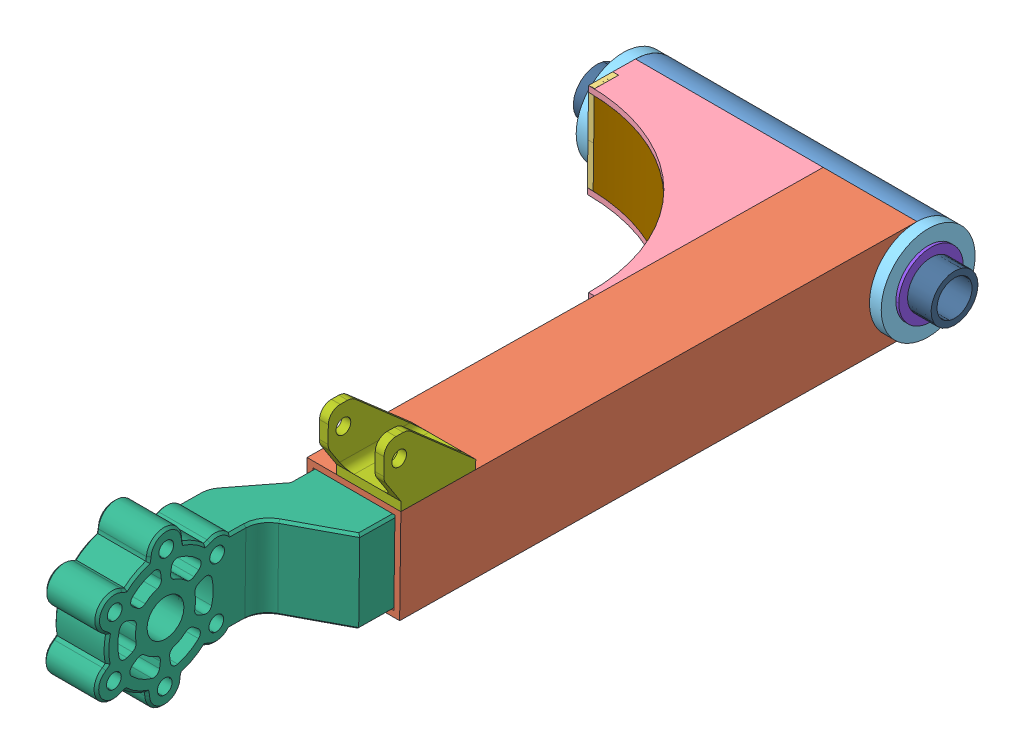
SolidWorks assembly Suspension set 2, configuration Default. Lengths in mm.
Overall size (193.67 103.89 441.92).
16 component instances, 13 part files, 36 mates.
Components (placement in the parent):
- SR 1 (2 inch)-1: SR 1 (2 inch) [Default] at (-137.0883 -10.8304 39.4879) size (152.4 50.8 50.8)
- SR (square tube)-1: SR (square tube) [Default] at (-10.0883 -10.8304 39.4879) x (1 0 0) z (0 0.013285 0.999912) size (50.8 50.8 279.4)
- Part1^Suspension set 2-1: Part1^Suspension set 2 [Default] at origin (virtual)
- Part2^Suspension set 2-1: Part2^Suspension set 2 [Default] at (-10.0883 14.5674 39.1505) x (1 0 0) z (0 0.999912 -0.013285) (virtual)
- Part3^Suspension set 2-1: Part3^Suspension set 2 [Default] at (-137.0883 -10.8304 39.4879) x (0 0 1) z (-1 0 0) size (13.73 50.97 3.17) (virtual)
- Part4^Suspension set 2-1: Part4^Suspension set 2 [Default] at origin (virtual)
- Gusset Rear Suspension set 2-1: Gusset Rear Suspension set 2 [Default] at (-65.1345 15.7769 130.1824) x (1 0 0) z (0 0.999912 -0.013285) size (101.6 123.82 3.17)
- Gusset Rear Suspension set 2-2: Gusset Rear Suspension set 2 [Default] at (-65.1345 -31.8439 130.8151) x (1 0 0) z (0 0.999912 -0.013285) size (101.6 123.82 3.17)
- SR (Cap)-1: SR (Cap) [Default] at (-143.4383 -10.8304 39.4879) x (-1 0 0) z (0 -0.74503 0.667031) size (19.05 50.8 50.8)
- SR (Cap)-2: SR (Cap) [Default] at (21.6617 -10.8304 39.4879) size (19.05 50.8 50.8)
- Cap insert-1: Cap insert [Default] at (12.1367 -29.1729 331.8574) x (-1 0 0) z (0 -0.013285 -0.999912) size (63.5 83.05 151.54)
- Brake Bracket-1: Brake Bracket [Default] at (-2.1508 22.8357 302.9889) x (-1 0 0) z (0 0.013285 0.999912) size (34.92 36.51 50)
- JFI-1618-12-1: JFI-1618-12 [Default] at (-145.0131 -10.8304 39.4879) x (0 0 -1) z (1 0 0) size (34.92 34.92 19.05)
- JFI-1618-12-2: JFI-1618-12 [Default] at (23.2365 -10.8304 39.4879) x (0 0 1) z (-1 0 0) size (34.92 34.92 19.05)
- Part5^Suspension set 2-1: Part5^Suspension set 2 [Default] at (-65.1345 -31.8439 130.8151) x (1 0 0) z (0 0.999912 -0.013285) size (98.42 101.55 44.45) (virtual)
- SR (axel)-1: SR (axel) [Default] at (-157.7258 -10.8304 39.4879) x (1 0 0) z (0 -0.238586 0.971121) size (193.68 25.4 25.4)
Mates (geometry in assembly coordinates):
- Concentric1: concentric anti-aligned: cylinder of SR 1 (2 inch)-1 through (15.3117 -10.8304 39.4879) axis (-1 0 0) radius 25.4; cylinder of SR (square tube)-1 through (-149.7883 -10.8304 39.4879) axis (1 0 0) radius 25.4
- Coincident1: coincident aligned: plane of SR 1 (2 inch)-1 through (15.3117 -10.8304 39.4879) normal (1 0 0); plane of SR (square tube)-1 through (15.3117 -32.5163 319.2007) normal (1 0 0)
- InPlace1: in place: plane of SR (square tube)-1 through (-35.4883 18.2792 318.5258) normal (0 0.999912 -0.013285); plane of ? through (0 14.0448 -0.1866) normal (0 0.999912 -0.013285); moOrthogonalPlaneRef_w of SR (square tube)-1 through (-35.4883 18.2792 318.5258) normal (0 0.999912 -0.013285); plane of ? through (0 14.0448 -0.1866) normal (0 -0.013285 -0.999912); plane of SR (square tube)-1 through (-35.4883 18.2792 318.5258) normal (0 0.999912 -0.013285); plane of ? through (0 14.0448 -0.1866) normal (1 0 0); plane of SR (square tube)-1 through (-35.4883 18.2792 318.5258) normal (0 0.999912 -0.013285); unknown of Part2^Suspension set 2-1
- Coincident2: coincident aligned: plane of SR (square tube)-1; plane of Part2^Suspension set 2-1
- Coincident3: coincident aligned: moOrthogonalPlaneRef_w of SR (square tube)-1 through (-10.0883 14.5674 39.1505) normal (0 -0.013285 -0.999912); plane of Part2^Suspension set 2-1 through (-10.0883 14.5674 39.1505) normal (0 -0.013285 -0.999912)
- Coincident4: coincident anti-aligned: moOrthogonalPlaneRef_w of SR (square tube)-1 through (-10.0883 14.5674 39.1505) normal (-1 0 0); plane of Part2^Suspension set 2-1 through (-10.0883 14.5674 39.1505) normal (1 0 0)
- InPlace2: in place: plane of SR 1 (2 inch)-1 through (-137.0883 -10.8304 39.4879) normal (-1 0 0); plane of ? through (-137.0883 0 0) normal (-1 0 0); plane of SR 1 (2 inch)-1 through (-137.0883 -10.8304 39.4879) normal (-1 0 0); plane of ? through (-137.0883 0 0) normal (0 1 0); plane of SR 1 (2 inch)-1 through (-137.0883 -10.8304 39.4879) normal (-1 0 0); plane of ? through (-137.0883 0 0) normal (0 0 1); plane of SR 1 (2 inch)-1 through (-137.0883 -10.8304 39.4879) normal (-1 0 0); unknown of Part3^Suspension set 2-1
- Coincident5: coincident aligned: plane of SR 1 (2 inch)-1; plane of Part3^Suspension set 2-1
- Coincident6: coincident aligned: moOrthogonalPlaneRef_w of SR 1 (2 inch)-1 through (-137.0883 -10.8304 39.4879) normal (0 1 0); plane of Part3^Suspension set 2-1 through (-137.0883 -10.8304 39.4879) normal (0 1 0)
- Coincident7: coincident anti-aligned: moOrthogonalPlaneRef_w of SR 1 (2 inch)-1 through (-137.0883 -10.8304 39.4879) normal (0 0 -1); plane of Part3^Suspension set 2-1 through (-137.0883 -10.8304 39.4879) normal (0 0 1)
- Coincident13: coincident anti-aligned: line of Part3^Suspension set 2-1 through (-137.0883 14.9048 64.5482) axis (0 -0.013285 -0.999912); line of Gusset Rear Suspension set 2-1 through (-137.0883 14.5674 39.1505) axis (0 0.013285 0.999912)
- Coincident26: coincident anti-aligned: line of Part3^Suspension set 2-1 through (-137.0883 -35.8907 65.2231) axis (0 -0.013285 -0.999912); line of Gusset Rear Suspension set 2-2 through (-137.0883 -36.2281 39.8253) axis (0 0.013285 0.999912)
- Coincident34: coincident aligned: plane of Part3^Suspension set 2-1 through (-137.0883 -10.8304 39.4879) normal (-1 0 0); plane of Gusset Rear Suspension set 2-2 through (-137.0883 -36.2281 39.8253) normal (-1 0 0)
- Coincident44: coincident anti-aligned: plane of SR 1 (2 inch)-1 through (-137.0883 -10.8304 39.4879) normal (-1 0 0); plane of SR (Cap)-1 through (-137.0883 -27.7729 20.5641) normal (1 0 0)
- Concentric2: concentric aligned: cylinder of SR 1 (2 inch)-1 through (15.3117 -10.8304 39.4879) axis (-1 0 0) radius 22.225; cylinder of SR (Cap)-1 through (-143.4383 -10.8304 39.4879) axis (-1 0 0) radius 22.225
- Concentric3: concentric anti-aligned: cylinder of SR 1 (2 inch)-1 through (15.3117 -10.8304 39.4879) axis (-1 0 0) radius 22.225; cylinder of SR (Cap)-2 through (21.6617 -10.8304 39.4879) axis (1 0 0) radius 22.225
- Coincident45: coincident anti-aligned: plane of SR 1 (2 inch)-1 through (15.3117 -10.8304 39.4879) normal (1 0 0); plane of SR (Cap)-2 through (15.3117 14.5696 39.4879) normal (-1 0 0)
- Coincident48: coincident anti-aligned: plane of SR (square tube)-1 through (-32.3133 -29.3416 319.1585) normal (1 0 0); plane of Cap insert-1 through (-32.3133 -29.679 293.7607) normal (-1 0 0)
- Coincident49: coincident anti-aligned: plane of SR (square tube)-1 through (-32.3133 15.1045 318.568) normal (0 -0.999912 0.013285); plane of Cap insert-1 through (12.1367 14.767 293.1702) normal (0 0.999912 -0.013285)
- Distance1: distance = 25.4 mm anti-aligned: plane of Cap insert-1 through (12.1367 -29.679 293.7607) normal (0 -0.013285 -0.999912); plane of SR (square tube)-1 through (-10.0883 -7.1186 318.8632) normal (0 0.013285 0.999912)
- Coincident51: coincident anti-aligned: plane of SR (square tube)-1 through (-35.4883 18.2792 318.5258) normal (0 0.999912 -0.013285); plane of Brake Bracket-1 through (-2.1508 18.0736 303.0522) normal (0 -0.999912 0.013285)
- Coincident52: coincident anti-aligned: line of SR (square tube)-1 through (15.3117 18.2792 318.5258) axis (0 -0.013285 -0.999912); line of Brake Bracket-1 through (15.3117 17.7415 278.0544) axis (0 0.013285 0.999912)
- Coincident53: coincident aligned: line of SR (square tube)-1 through (15.3117 18.2792 318.5258) axis (-1 0 0); line of Brake Bracket-1 through (15.3117 18.2792 318.5258) axis (-1 0 0)
- Coincident54: coincident anti-aligned: plane of SR (Cap)-1 through (-143.4383 -20.3606 28.8433) normal (-1 0 0); plane of JFI-1618-12-1 through (-143.4383 -10.8304 23.3629) normal (1 0 0)
- Concentric4: concentric anti-aligned: cylinder of SR (Cap)-1 through (-143.4383 -10.8304 39.4879) axis (-1 0 0) radius 14.2875; cylinder of JFI-1618-12-1 through (-135.4881 -10.8304 39.4879) axis (1 0 0) radius 12.7
- Coincident55: coincident anti-aligned: plane of SR (Cap)-2 through (21.6617 3.4571 39.4879) normal (1 0 0); plane of JFI-1618-12-2 through (21.6617 -10.8304 55.6129) normal (-1 0 0)
- Concentric5: concentric anti-aligned: cylinder of SR (Cap)-2 through (21.6617 -10.8304 39.4879) axis (1 0 0) radius 14.2875; cylinder of JFI-1618-12-2 through (13.0741 -10.8304 39.4879) axis (-1 0 0) radius 14.2875
- Coincident56: coincident aligned: line of Part3^Suspension set 2-1 through (-133.9133 -10.4929 64.8857) axis (0 -0.999912 0.013285); line of Part7^Suspension set 2-1 through (-133.9133 11.7301 64.5904) axis (0 -0.999912 0.013285)
- Coincident59: coincident anti-aligned: plane of Gusset Rear Suspension set 2-1 through (-137.0883 13.0377 163.0067) normal (0 -0.999912 0.013285); plane of Part7^Suspension set 2-1 through (-137.0883 13.0377 163.0067) normal (0 0.999912 -0.013285)
- Coincident60: coincident anti-aligned: line of SR (square tube)-1 through (-35.4883 -36.2281 39.8253) axis (1 0 0); line of Gusset Rear Suspension set 2-2 through (-35.4883 -36.2281 39.8253) axis (-1 0 0)
- InPlace3: in place: plane of ? through (-137.0883 -31.4084 163.5972) normal (0 0.999912 -0.013285); plane of ? through (0 -33.576 0.4461) normal (0 0.999912 -0.013285); plane of ? through (-137.0883 -31.4084 163.5972) normal (0 0.999912 -0.013285); plane of ? through (0 -33.576 0.4461) normal (0 -0.013285 -0.999912); plane of ? through (-137.0883 -31.4084 163.5972) normal (0 0.999912 -0.013285); plane of ? through (0 -33.576 0.4461) normal (1 0 0); plane of ? through (-137.0883 -31.4084 163.5972) normal (0 0.999912 -0.013285); unknown of ?
- Coincident61: coincident aligned: plane of Gusset Rear Suspension set 2-2; plane of Part5^Suspension set 2-1
- Coincident62: coincident aligned: moOrthogonalPlaneRef_w of Gusset Rear Suspension set 2-2 through (-65.1345 -31.8439 130.8151) normal (0 -0.013285 -0.999912); plane of Part5^Suspension set 2-1 through (-65.1345 -31.8439 130.8151) normal (0 -0.013285 -0.999912)
- Coincident63: coincident anti-aligned: moOrthogonalPlaneRef_w of Gusset Rear Suspension set 2-2 through (-65.1345 -31.8439 130.8151) normal (-1 0 0); plane of Part5^Suspension set 2-1 through (-65.1345 -31.8439 130.8151) normal (1 0 0)
- Concentric6: concentric anti-aligned: cylinder of JFI-1618-12-1 through (-135.4881 -10.8304 39.4879) axis (1 0 0) radius 12.7; cylinder of SR (axel)-1 through (35.9492 -10.8304 39.4879) axis (-1 0 0) radius 12.7
- Distance2: distance = 14.2875 mm aligned: plane of SR (axel)-1 through (-157.7258 -10.8304 39.4879) normal (-1 0 0); plane of SR (Cap)-1 through (-143.4383 -20.3606 28.8433) normal (-1 0 0)
